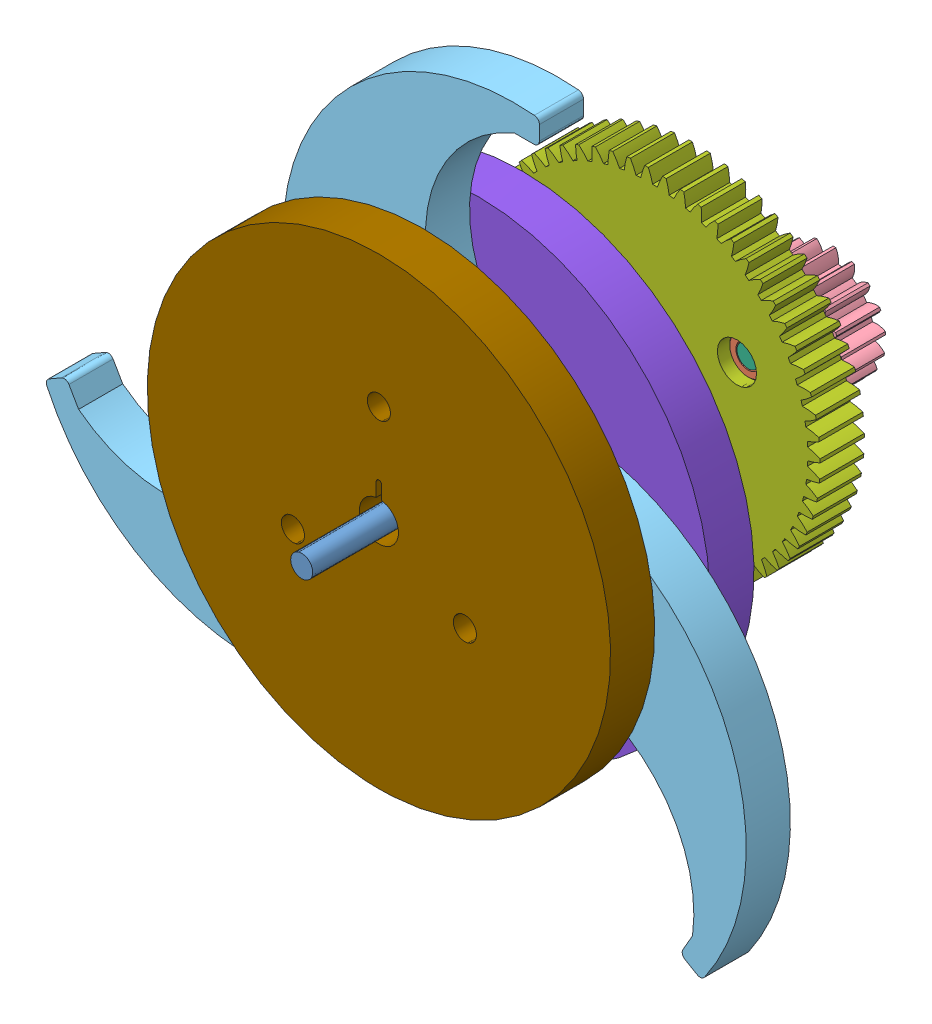
SolidWorks assembly GearSet2-Right, configuration Default. Lengths in mm.
Overall size (130.95 132.75 80).
30 component instances, 9 part files, 42 mates.
Components (placement in the parent):
- Shaft4x55-1: Shaft4x55 [Default] at (30.5179 39.8122 29.3987) size (4 4 80)
- Bearing4x7x2.5-1: Bearing4x7x2.5 [Default] at (30.5179 39.8122 43.8987) x (0.886811 0.462132 0) z (0 0 1) size (7 7 2.5)
- Bearing4x7x2.5-2: Bearing4x7x2.5 [Default] at (30.5179 39.8122 38.3987) x (0.973436 0.22896 0) z (0 0 1) size (7 7 2.5)
- Gear 1M 30T D7 Holder-Assem-1: Gear 1M 30T D7 Holder-Assem [Default] at (30.5179 39.8122 58.3987) x (0 0 1) z (1 0 0) size (8 31.88 32)
- Bearing4x7x2.5-3: Bearing4x7x2.5 [Default] at (30.5179 39.8122 74.8987) size (7 7 2.5)
- Bearing4x7x2.5-4: Bearing4x7x2.5 [Default] at (30.5179 39.8122 63.8987) size (7 7 2.5)
- Bearing4x7x2.5-5: Bearing4x7x2.5 [Default] at (30.5179 39.8122 58.3987) size (7 7 2.5)
- Bearing4x7x2.5-6: Bearing4x7x2.5 [Default] at (30.5179 39.8122 67.1869) size (7 7 2.5)
- Bearing4x7x2.5-7: Bearing4x7x2.5 [Default] at (30.5179 39.8122 47.3987) x (0.886811 0.462132 0) z (0 0 1) size (7 7 2.5)
- Bearing4x7x2.5-8: Bearing4x7x2.5 [Default] at (30.5179 39.8122 54.8987) x (0.886811 0.462132 0) z (0 0 1) size (7 7 2.5)
- Gear 1M 18T D4-Assem-3: Gear 1M 18T D4-Assem [Default] at (30.5179 39.8122 37.3987) x (0 0 -1) z (-0.600838 -0.79937 0) size (8 19.78 20)
- WheelClawPrinted-1: WheelClawPrinted [Default] at (46.1063 66.8122 96.3987) x (0.5 -0.866025 0) z (0.866025 0.5 0) size (51.89 8 66.01)
- WheelClawPrinted-2: WheelClawPrinted [Default] at (-0.6591 39.8122 96.3987) x (0.5 0.866025 0) z (-0.866025 0.5 0) size (51.89 8 66.01)
- WheelClawPrinted-3: WheelClawPrinted [Default] at (46.1063 12.8122 96.3987) x (-1 0 0) z (0 -1 0) size (51.89 8 66.01)
- Bearing4x7x2.5-9: Bearing4x7x2.5 [Default] at (46.4234 48.2391 41.8987) size (7 7 2.5)
- Shaft4x15-1: Shaft4x15 [Default] at (46.4234 48.2391 44.3987) x (0.934634 0.35561 0) z (0 0 -1) size (4 4 15)
- Bearing4x7x2.5-10: Bearing4x7x2.5 [Default] at (46.4234 48.2391 39.3987) size (7 7 2.5)
- Gear 1M 18T D4-Assem-6: Gear 1M 18T D4-Assem [Default] at (30.5179 39.8122 86.3987) x (0 0 -1) z (-0.600838 -0.79937 0) size (8 19.78 20)
- Gear 1M 60T D7 Holder-Assem-1: Gear 1M 60T D7 Holder-Assem [Default] at (30.5179 39.8122 38.3987) x (0 0 1) z (0.999338 -0.036383 0) size (8 61.95 61.95)
- Gear 1M 18T D4-Assem-7: Gear 1M 18T D4-Assem [Default] at (46.4234 48.2391 37.3987) x (0 0 -1) z (-0.405314 -0.914178 0) size (8 19.78 20)
- Bearing4x7x2.5-15: Bearing4x7x2.5 [Default] at (15.2672 49.3734 41.8987) x (-0.5 0.866025 0) z (0 0 1) size (7 7 2.5)
- Bearing4x7x2.5-16: Bearing4x7x2.5 [Default] at (29.863 21.8241 41.8987) x (-0.5 -0.866025 0) z (0 0 1) size (7 7 2.5)
- Shaft4x15-4: Shaft4x15 [Default] at (15.2672 49.3734 44.3987) x (-0.775285 0.631612 0) z (0 0 -1) size (4 4 15)
- Shaft4x15-5: Shaft4x15 [Default] at (29.863 21.8241 44.3987) x (-0.15935 -0.987222 0) z (0 0 -1) size (4 4 15)
- Bearing4x7x2.5-17: Bearing4x7x2.5 [Default] at (15.2672 49.3734 39.3987) x (-0.5 0.866025 0) z (0 0 1) size (7 7 2.5)
- Bearing4x7x2.5-18: Bearing4x7x2.5 [Default] at (29.863 21.8241 39.3987) x (-0.5 -0.866025 0) z (0 0 1) size (7 7 2.5)
- Gear 1M 18T D4-Assem-8: Gear 1M 18T D4-Assem [Default] at (15.2672 49.3734 37.3987) x (0 0 -1) z (0.994358 0.106077 0) size (8 19.78 20)
- Gear 1M 18T D4-Assem-9: Gear 1M 18T D4-Assem [Default] at (29.863 21.8241 37.3987) x (0 0 -1) z (-0.589044 0.808101 0) size (8 19.78 20)
- WheelHolderMirrored-1: WheelHolderMirrored [Default] at (30.5179 39.8122 69.3987) x (-1 0 0) z (0 1 0) size (84 11 84)
- WheelHolder-OutMirrored-1: WheelHolder-OutMirrored [Default] at (30.5179 39.8122 95.3987) x (1 0 0) z (0 1 0) size (84 26 84)
Mates (geometry in assembly coordinates):
- Concentric3: concentric aligned: cylinder of Shaft4x55-1 through (30.5179 39.8122 109.3987) axis (0 0 -1) radius 2; cylinder of Bearing4x7x2.5-1 through (30.5179 39.8122 46.3987) axis (0 0 -1) radius 2
- Concentric7: concentric aligned: cylinder of Gear 1M 30T D7 Holder-Assem-1 through (30.5179 39.8122 108.3987) axis (0 0 -1) radius 3.5; cylinder of Bearing4x7x2.5-5 through (30.5179 39.8122 60.8987) axis (0 0 -1) radius 3.5
- Coincident6: coincident aligned: plane of Gear 1M 30T D7 Holder-Assem-1 through (30.5179 39.8122 58.3987) normal (0 0 -1); plane of Bearing4x7x2.5-5 through (30.5179 39.8122 58.3987) normal (0 0 -1)
- Concentric8: concentric aligned: cylinder of Gear 1M 30T D7 Holder-Assem-1 through (30.5179 39.8122 108.3987) axis (0 0 -1) radius 3.5; cylinder of Bearing4x7x2.5-4 through (30.5179 39.8122 66.3987) axis (0 0 -1) radius 3.5
- Coincident7: coincident aligned: plane of Gear 1M 30T D7 Holder-Assem-1 through (30.5179 39.8122 66.3987) normal (0 0 1); plane of Bearing4x7x2.5-4 through (30.5179 39.8122 66.3987) normal (0 0 1)
- Concentric9: concentric aligned: cylinder of Shaft4x55-1 through (30.5179 39.8122 109.3987) axis (0 0 -1) radius 2; cylinder of Bearing4x7x2.5-4 through (30.5179 39.8122 66.3987) axis (0 0 -1) radius 2
- Concentric10: concentric aligned: cylinder of Shaft4x55-1 through (30.5179 39.8122 109.3987) axis (0 0 -1) radius 2; cylinder of Bearing4x7x2.5-3 through (30.5179 39.8122 77.3987) axis (0 0 -1) radius 2
- Concentric14: concentric aligned: cylinder of Shaft4x55-1 through (30.5179 39.8122 109.3987) axis (0 0 -1) radius 2; cylinder of Bearing4x7x2.5-8 through (30.5179 39.8122 57.3987) axis (0 0 -1) radius 2
- Concentric15: concentric aligned: cylinder of Shaft4x55-1 through (30.5179 39.8122 109.3987) axis (0 0 -1) radius 2; cylinder of Bearing4x7x2.5-7 through (30.5179 39.8122 49.8987) axis (0 0 -1) radius 2
- Distance3: distance = 10 mm anti-aligned: plane of Bearing4x7x2.5-7 through (30.5179 39.8122 47.3987) normal (0 0 -1); plane of Bearing4x7x2.5-8 through (30.5179 39.8122 57.3987) normal (0 0 1)
- Distance4: distance = 1 mm anti-aligned: plane of Bearing4x7x2.5-7 through (30.5179 39.8122 47.3987) normal (0 0 -1); plane of Bearing4x7x2.5-1 through (30.5179 39.8122 46.3987) normal (0 0 1)
- Distance5: distance = 1 mm anti-aligned: plane of Bearing4x7x2.5-5 through (30.5179 39.8122 58.3987) normal (0 0 -1); plane of Bearing4x7x2.5-8 through (30.5179 39.8122 57.3987) normal (0 0 1)
- Concentric20: concentric anti-aligned: cylinder of Shaft4x55-1 through (30.5179 39.8122 109.3987) axis (0 0 -1) radius 2; cylinder of Gear 1M 18T D4-Assem-3 through (30.5179 39.8122 -12.6014) axis (0 0 1) radius 2
- Coincident11: coincident aligned: plane of Shaft4x55-1 through (30.5179 39.8122 29.3987) normal (0 0 -1); plane of Gear 1M 18T D4-Assem-3 through (30.5179 39.8122 29.3987) normal (0 0 -1)
- Concentric24: concentric anti-aligned: cylinder of Bearing4x7x2.5-9 through (46.4234 48.2391 44.3987) axis (0 0 -1) radius 2; cylinder of Shaft4x15-1 through (46.4234 48.2391 29.3987) axis (0 0 1) radius 2
- Concentric25: concentric anti-aligned: cylinder of Shaft4x15-1 through (46.4234 48.2391 29.3987) axis (0 0 1) radius 2; cylinder of Bearing4x7x2.5-10 through (46.4234 48.2391 41.8987) axis (0 0 -1) radius 2
- Coincident17: coincident aligned: plane of Bearing4x7x2.5-9 through (46.4234 48.2391 44.3987) normal (0 0 1); plane of Shaft4x15-1 through (46.4234 48.2391 44.3987) normal (0 0 1)
- Coincident18: coincident anti-aligned: plane of Bearing4x7x2.5-9 through (46.4234 48.2391 41.8987) normal (0 0 -1); plane of Bearing4x7x2.5-10 through (46.4234 48.2391 41.8987) normal (0 0 1)
- Concentric26: concentric anti-aligned: cylinder of Shaft4x55-1 through (30.5179 39.8122 109.3987) axis (0 0 -1) radius 2; cylinder of Gear 1M 18T D4-Assem-6 through (30.5179 39.8122 36.3986) axis (0 0 1) radius 2
- Concentric28: concentric aligned: cylinder of Bearing4x7x2.5-1 through (30.5179 39.8122 46.3987) axis (0 0 -1) radius 3.5; cylinder of Gear 1M 60T D7 Holder-Assem-1 through (30.5179 39.8122 88.3987) axis (0 0 -1) radius 3.55
- Coincident20: coincident aligned: plane of Bearing4x7x2.5-1 through (30.5179 39.8122 46.3987) normal (0 0 1); plane of Gear 1M 60T D7 Holder-Assem-1 through (30.5179 39.8122 46.3987) normal (0 0 1)
- Coincident21: coincident aligned: plane of Bearing4x7x2.5-2 through (30.5179 39.8122 38.3987) normal (0 0 -1); plane of Gear 1M 60T D7 Holder-Assem-1 through (30.5179 39.8122 38.3987) normal (0 0 -1)
- Concentric29: concentric aligned: cylinder of Shaft4x55-1 through (30.5179 39.8122 109.3987) axis (0 0 -1) radius 2; cylinder of Bearing4x7x2.5-2 through (30.5179 39.8122 40.8987) axis (0 0 -1) radius 3.5
- Distance10: distance = 1 mm anti-aligned: plane of Gear 1M 60T D7 Holder-Assem-1 through (30.5179 39.8122 38.3987) normal (0 0 -1); plane of Gear 1M 18T D4-Assem-3 through (30.5179 39.8122 37.3987) normal (0 0 1)
- Concentric30: concentric anti-aligned: cylinder of Bearing4x7x2.5-10 through (46.4234 48.2391 41.8987) axis (0 0 -1) radius 3.5; cylinder of Gear 1M 60T D7 Holder-Assem-1 through (46.4234 48.2391 36.3987) axis (0 0 1) radius 3.55
- Coincident23: coincident anti-aligned: cylinder of Shaft4x15-1 through (46.4234 48.2391 29.3987) axis (0 0 1) radius 2; circle of Gear 1M 18T D4-Assem-7
- Coincident24: coincident aligned: plane of Shaft4x15-1 through (46.4234 48.2391 29.3987) normal (0 0 -1); plane of Gear 1M 18T D4-Assem-7 through (46.4234 48.2391 29.3987) normal (0 0 -1)
- Distance11: distance = 1 mm aligned: plane of Gear 1M 60T D7 Holder-Assem-1 through (30.5179 39.8122 38.3987) normal (0 0 -1); plane of Bearing4x7x2.5-10 through (46.4234 48.2391 39.3987) normal (0 0 -1)
- Coincident26: coincident aligned: plane of Gear 1M 18T D4-Assem-3 through (34.2744 36.4882 39.3987) normal (0.600838 0.79937 0); plane of Gear 1M 18T D4-Assem-6 through (34.2744 36.4882 88.3987) normal (0.600838 0.79937 0)
- GearMate2: gear = 20 : 20 mm: cylinder of Gear 1M 18T D4-Assem-7 through (46.4234 48.2391 47.3987) axis (0 0 1) radius 10; cylinder of Gear 1M 18T D4-Assem-3 through (30.5179 39.8122 47.3987) axis (0 0 1) radius 10
- Parallel1: parallel anti-aligned: plane of Gear 1M 30T D7 Holder-Assem-1 through (31.0179 45.8122 68.3987) normal (-1 0 0)
- GearMate3: gear = 20 : 20 mm: cylinder of WheelClawPrinted-1 through (30.5179 57.8122 78.3987) axis (0 0 1) radius 10; cylinder of Gear 1M 18T D4-Assem-6 through (30.5179 39.8122 96.3987) axis (0 0 1) radius 10
- Concentric31: concentric aligned: cylinder of Bearing4x7x2.5-6 through (30.5179 39.8122 69.6869) axis (0 0 -1) radius 3.5; cylinder of WheelHolderMirrored-1 through (30.5179 39.8122 77.3987) axis (0 0 -1) radius 3.55
- Concentric32: concentric anti-aligned: cylinder of Shaft4x55-1 through (30.5179 39.8122 109.3987) axis (0 0 -1) radius 2; circle of Bearing4x7x2.5-6
- Coincident27: coincident anti-aligned: line of Gear 1M 30T D7 Holder-Assem-1 through (31.0179 45.8122 66.3987) axis (0 -1 0); line of WheelHolderMirrored-1 through (31.0179 43.3268 66.3987) axis (0 1 0)
- Concentric33: concentric anti-aligned: cylinder of WheelClawPrinted-1 through (30.5179 57.8122 78.3987) axis (0 0 1) radius 3.55; cylinder of WheelHolderMirrored-1 through (30.5179 57.8122 77.3987) axis (0 0 -1) radius 1.95
- Concentric34: concentric anti-aligned: cylinder of Shaft4x55-1 through (30.5179 39.8122 109.3987) axis (0 0 -1) radius 2; circle of WheelHolder-OutMirrored-1
- Coincident29: coincident aligned: plane of WheelHolderMirrored-1 through (30.5179 39.8122 69.3987) normal (0 0 -1); plane of WheelHolder-OutMirrored-1 through (30.5179 39.8122 69.3987) normal (0 0 -1)
- Coincident30: coincident aligned: plane of WheelHolderMirrored-1 through (31.0179 46.8122 67.3987) normal (-1 0 0); plane of WheelHolder-OutMirrored-1 through (31.0179 45.8122 97.3987) normal (-1 0 0)
- Distance12: distance = 1 mm anti-aligned: plane of WheelClawPrinted-1 through (30.5179 57.8122 78.3987) normal (0 0 -1); plane of WheelHolderMirrored-1 through (30.5179 39.8122 77.3987) normal (0 0 1)
- Coincident32: coincident aligned: plane of WheelClawPrinted-1 through (30.5179 57.8122 86.3987) normal (0 0 1); plane of Gear 1M 18T D4-Assem-6 through (30.5179 39.8122 86.3987) normal (0 0 1)
- LimitAngle1: limit planar angle = 0 rad aligned: plane of WheelHolderMirrored-1 through (46.1063 46.6122 42.3987) normal (-1 0 0); plane of WheelClawPrinted-3 through (46.1063 49.5135 78.3987) normal (-1 0 0)
